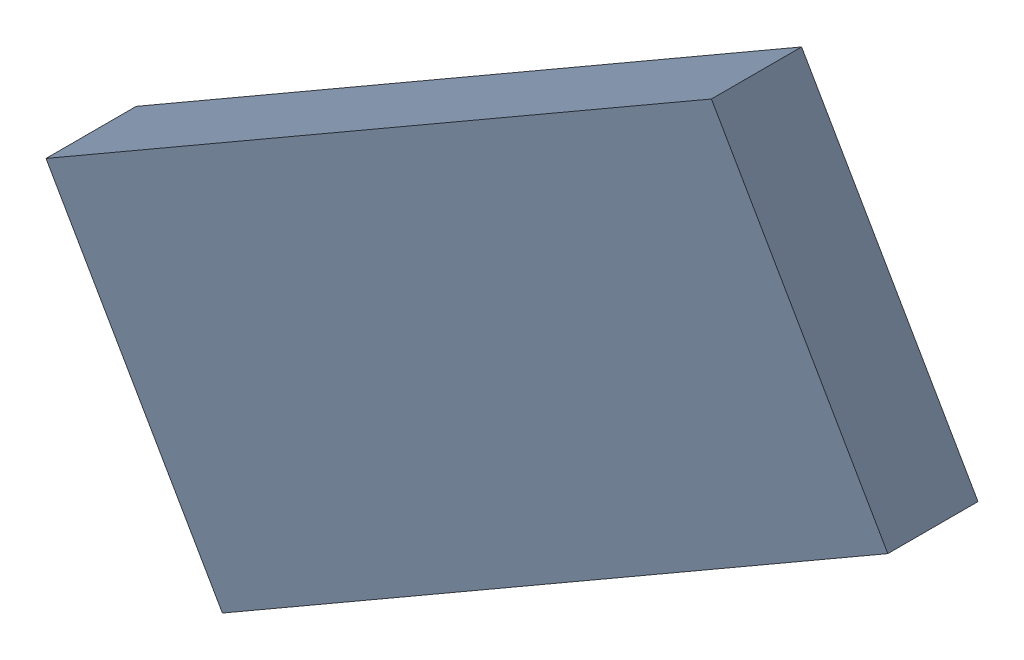
SolidWorks assembly TDA5340_TDA2, configuration Standard. Lengths in mm.
Overall size (10.74 8.8 1.15).
2 component instances, 1 part files, 0 mates.
Components (placement in the parent):
- 885544280-1: 885544280 [Standard] at (41.9925 27.6621 0.05) size (10.74 8.8 1.15)
  - Extruded_12-1: Extruded_12 [Standard] at origin size (10.74 8.8 1.15)
